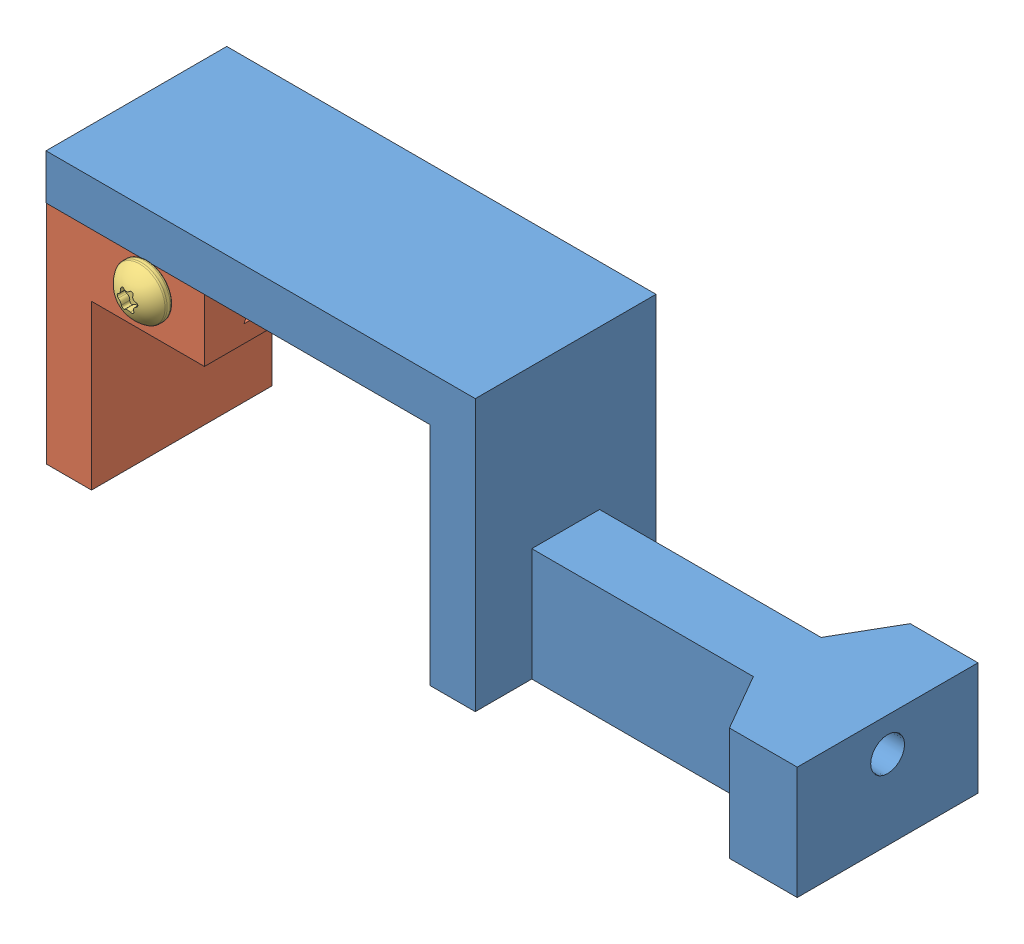
SolidWorks assembly Brain_Holder_Assembly, configuration Default. Lengths in mm.
Overall size (33.25 12 10.21).
4 component instances, 3 part files, 6 mates.
Components (placement in the parent):
- Brain_Holder_Top-1: Brain_Holder_Top [Default] at (6.2228 15.1489 20.4206) size (33.25 12 8)
- Brain_Holder_Bottom-1: Brain_Holder_Bottom [Default] at (7.2363 15.1489 20.4206) size (7 10 8)
- 96001A053_18-8 SS TORX THREAD-FORMING SCREW FOR PLASTIC-1: 96001A053_18-8 SS TORX THREAD-FORMING SCREW FOR PLASTIC [96001A053] at (2.2163 16.6117 22.8331) x (0.836154 0.548495 0) z (0 0 1) size (2.29 2.29 4.91)
- 96001A053_18-8 SS TORX THREAD-FORMING SCREW FOR PLASTIC-2: 96001A053_18-8 SS TORX THREAD-FORMING SCREW FOR PLASTIC [96001A053] at (2.2163 16.6117 18.0081) x (-0.543538 -0.839385 0) z (0 0 -1) size (2.29 2.29 4.91)
Mates (geometry in assembly coordinates):
- Coincident3: coincident: plane of Brain_Holder_Top-1 through (6.2228 15.1489 24.4206) normal (0 0 1); plane of Brain_Holder_Bottom-1 through (7.2363 15.1489 24.4206) normal (0 0 1)
- Concentric1: concentric: circle of Brain_Holder_Bottom-1; circle of 96001A053_18-8 SS TORX THREAD-FORMING SCREW FOR PLASTIC-1
- Concentric2: concentric: circle of Brain_Holder_Bottom-1; circle of 96001A053_18-8 SS TORX THREAD-FORMING SCREW FOR PLASTIC-2
- Coincident4: coincident: plane of Brain_Holder_Top-1 through (-2.2772 17.6489 16.4196) normal (0 -1 0); plane of Brain_Holder_Bottom-1 through (-2.2647 17.6489 24.4206) normal (0 1 0)
- Coincident5: coincident: plane of Brain_Holder_Bottom-1 through (7.2363 15.1489 16.4206) normal (0 0 -1); plane of 96001A053_18-8 SS TORX THREAD-FORMING SCREW FOR PLASTIC-2 through (2.2163 16.6117 16.4206) normal (0 0 1)
- Coincident6: coincident: plane of Brain_Holder_Bottom-1 through (7.2363 15.1489 24.4206) normal (0 0 1); plane of 96001A053_18-8 SS TORX THREAD-FORMING SCREW FOR PLASTIC-1 through (2.2163 16.6117 24.4206) normal (0 0 -1)
